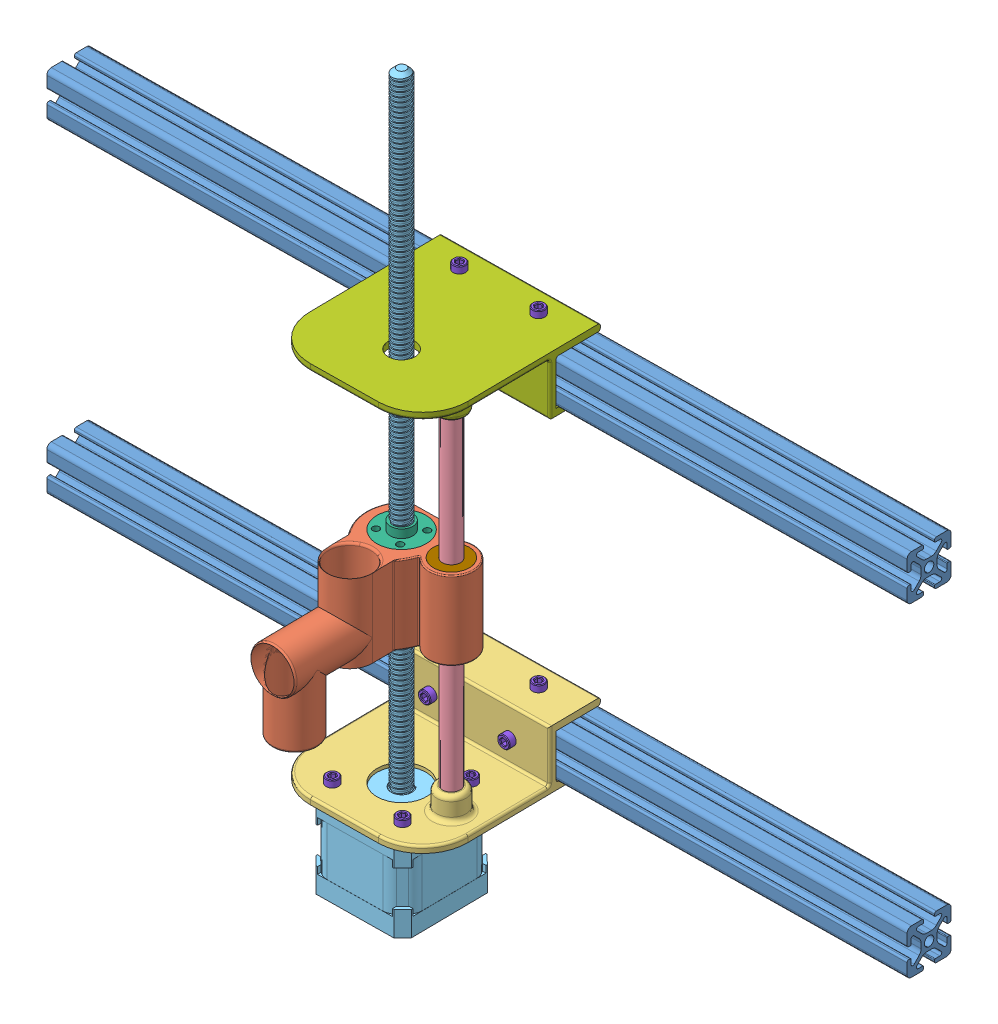
SolidWorks assembly Assem2, configuration Default. Lengths in mm.
Overall size (380.24 318.5 115.27).
26 component instances, 9 part files, 62 mates.
Components (placement in the parent):
- 8020-380.020400mm-1: 8020-380.020400mm [Default] at (296.7337 127.1693 232.1111) x (0.012782 0 0.999918) z (-0.999918 0 0.012782) size (19.99 19.99 380.02)
- Part3-1: Part3 [Default] at (107.463 220.2256 291.1801) x (-0.999918 0 0.012782) z (-0.012782 0 -0.999918) size (48.24 55.74 71)
- Part4-1: Part4 [Default] at (107.1224 114.1744 264.5322) x (0.012782 0 0.999918) z (-0.999918 0 0.012782) size (80 26 70)
- Part2-1: Part2 [Default] at (129.3015 117.1744 278.3999) x (0.999993 0 -0.003845) z (0.003845 0 0.999993) size (8 165 8)
- Pololu Stepper with 280mm LeadScrew-1: Pololu Stepper with 280mm LeadScrew [Valor predeterminado] at (107.3033 106.1744 278.6811) x (0.999918 0 -0.012782) z (0.012782 0 0.999918) size (42.3 318.5 42.3)
- TravelingNut-1: TravelingNut [Valor predeterminado] at (107.3033 213.2256 278.6811) x (0.998376 0 0.056964) z (-0.056964 0 0.998376) size (22 13.66 22)
- Part5-1: Part5 [Default] at (107.1224 285.154 264.5322) x (0.012782 0 0.999918) z (0.999918 0 -0.012782) size (80 26 70)
- 8020-380.020400mm-2: 8020-380.020400mm [Default] at (296.7337 272.1591 232.1111) x (0 1 0) z (-0.999918 0 0.012782) size (19.99 19.99 380.02)
- M3x10-1: M3x10 [Default] at (123.0001 120.1744 293.9817) x (0 -1 0) z (0.006337 0 0.99998) size (13 5.5 5.5)
- M3x10-2: M3x10 [Default] at (122.6039 120.1744 262.9842) x (0 -1 0) z (0 0 1) size (13 5.5 5.5)
- M3x10-3: M3x10 [Default] at (91.6064 120.1744 263.3805) x (0 -1 0) z (0 0 1) size (13 5.5 5.5)
- M3x10-4: M3x10 [Default] at (92.0026 120.1744 294.3779) x (0 -1 0) z (0 0 1) size (13 5.5 5.5)
- M3x10-5: M3x10 [Default] at (89.4449 127.1744 250.7571) x (-0.012782 0 -0.999918) z (0.974465 -0.224194 -0.012456) size (13 5.5 5.5)
- M3x10-6: M3x10 [Default] at (124.442 127.1744 250.3097) x (-0.012782 0 -0.999918) z (0.974868 -0.222434 -0.012462) size (13 5.5 5.5)
- M3x10-7: M3x10 [Default] at (124.2375 143.1744 234.311) x (0 -1 0) z (0 0 1) size (13 5.5 5.5)
- M3x10-8: M3x10 [Default] at (89.2404 143.1744 234.7584) x (0 -1 0) z (0 0 1) size (13 5.5 5.5)
- M3x10-9: M3x10 [Default] at (89.4449 272.154 250.7571) x (-0.012782 0 -0.999918) z (0.982593 0.185347 -0.01256) size (13 5.5 5.5)
- M3x10-10: M3x10 [Default] at (124.442 272.154 250.3097) x (-0.012782 0 -0.999918) z (0.982593 0.185347 -0.01256) size (13 5.5 5.5)
- M3x10-11: M3x10 [Default] at (124.2375 288.154 234.311) x (0 -1 0) z (-0.816398 0 -0.57749) size (13 5.5 5.5)
- M3x10-12: M3x10 [Default] at (89.2404 256.154 234.7584) x (0 1 0) z (0.795512 0 0.605938) size (13 5.5 5.5)
- M3x10-13: M3x10 [Default] at (89.2404 288.154 234.7584) x (0 -1 0) z (0.325387 0 -0.945581) size (13 5.5 5.5)
- M3x10-14: M3x10 [Default] at (124.2375 256.154 234.311) x (0 1 0) z (0 0 1) size (13 5.5 5.5)
- M3x10-15: M3x10 [Default] at (124.2375 111.1744 234.311) x (0 1 0) z (0 0 1) size (13 5.5 5.5)
- M3x10-16: M3x10 [Default] at (89.2404 111.1744 234.7584) x (0 1 0) z (0 0 1) size (13 5.5 5.5)
- 6659K679_OIL-EMBEDDED FLANGED SLEEVE BEARING-1: 6659K679_OIL-EMBEDDED FLANGED SLEEVE BEARING [6659K679] at (129.3015 180.2256 278.3999) size (16 16 16)
- 6659K679_OIL-EMBEDDED FLANGED SLEEVE BEARING-2: 6659K679_OIL-EMBEDDED FLANGED SLEEVE BEARING [6659K679] at (129.3015 215.2256 278.3999) x (-0.523048 0 -0.852303) z (-0.852303 0 0.523048) size (16 16 16)
Mates (geometry in assembly coordinates):
- Width1: width anti-aligned: plane of 8020-380.020400mm-1 through (-83.2702 133.7944 235.8351) normal (-0.999918 0 0.012782); plane of Part4-1 through (296.7192 133.7944 230.9778) normal (0.999918 0 -0.012782); plane of 8020-380.020400mm-1 through (142.1195 117.1744 264.0849) normal (0.999918 0 -0.012782); plane of Part4-1 through (72.1253 117.1744 264.9796) normal (-0.999918 0 0.012782)
- Coincident23: coincident anti-aligned: plane of 8020-380.020400mm-1 through (-83.3578 117.1744 228.9808) normal (0 -1 0); plane of Part4-1 through (107.1224 117.1744 264.5322) normal (0 1 0)
- Coincident24: coincident anti-aligned: plane of 8020-380.020400mm-1 through (-83.1279 119.181 246.9625) normal (0.012782 0 0.999918); plane of Part4-1 through (106.8668 140.1744 244.5339) normal (-0.012782 0 -0.999918)
- Parallel3: parallel aligned: plane of 8020-380.020400mm-1 through (-83.1536 137.1642 244.9561) normal (0 1 0); plane of 8020-380.020400mm-2 through (-83.1536 282.154 244.9561) normal (0 1 0)
- Distance2: distance = 125 mm anti-aligned: plane of 8020-380.020400mm-2 through (-83.3578 262.1642 228.9808) normal (0 -1 0); plane of 8020-380.020400mm-1 through (-83.3578 137.1642 228.9808) normal (0 1 0)
- Coincident33: coincident aligned: plane of 8020-380.020400mm-1 through (-83.1279 135.1576 246.9625) normal (0.012782 0 0.999918); plane of 8020-380.020400mm-2 through (-83.1279 264.1708 246.9625) normal (0.012782 0 0.999918)
- Coincident34: coincident aligned: plane of 8020-380.020400mm-1 through (-83.2702 133.7944 235.8351) normal (-0.999918 0 0.012782); plane of 8020-380.020400mm-2 through (-83.3403 271.0257 230.3439) normal (-0.999918 0 0.012782)
- Concentric14: concentric anti-aligned: cylinder of Part3-1 through (107.3033 211.2256 278.6811) axis (0 1 0) radius 11; cylinder of TravelingNut-1 through (107.3033 215.2256 278.6811) axis (0 -1 0) radius 11
- Coincident19: coincident anti-aligned: plane of Part3-1 through (107.463 211.2256 291.1801) normal (0 1 0); plane of TravelingNut-1 through (107.3033 211.2256 278.6811) normal (0 -1 0)
- Concentric39: concentric anti-aligned: cylinder of Part3-1 through (129.3015 199.2256 278.3999) axis (0 1 0) radius 6; cylinder of Part7-2 through (129.3015 215.2256 278.3999) axis (0 -1 0) radius 6
- Coincident63: coincident anti-aligned: plane of Part3-1 through (107.463 199.2256 291.1801) normal (0 1 0); plane of Part7-2 through (129.3015 199.2256 278.3999) normal (0 -1 0)
- Concentric41: concentric aligned: cylinder of Part3-1 through (129.3015 196.2256 278.3999) axis (0 -1 0) radius 6; cylinder of Part7-1 through (129.3015 196.2256 278.3999) axis (0 -1 0) radius 6
- Coincident65: coincident anti-aligned: plane of Part3-1 through (107.463 196.2256 291.1801) normal (0 -1 0); plane of Part7-1 through (129.3015 196.2256 278.3999) normal (0 1 0)
- Coincident18: coincident anti-aligned: plane of Part4-1 through (107.1224 114.1744 264.5322) normal (0 -1 0); plane of Pololu Stepper with 280mm LeadScrew-1 through (107.3033 114.1744 278.6811) normal (0 1 0)
- Concentric11: concentric anti-aligned: cylinder of Part4-1 through (107.3033 107.1744 278.6811) axis (0 1 0) radius 11.025; cylinder of Pololu Stepper with 280mm LeadScrew-1 through (107.3033 115.6744 278.6811) axis (0 -1 0) radius 11
- Concentric12: concentric aligned: circle of Part4-1; cylinder of Pololu Stepper with 280mm LeadScrew-1 through (92.0026 89.1744 294.3779) axis (0 1 0) radius 1.8537
- Concentric16: concentric aligned: cylinder of Part4-1 through (129.3015 127.1744 278.3999) axis (0 -1 0) radius 4; cylinder of Part2-1 through (129.3015 282.1744 278.3999) axis (0 -1 0) radius 4
- Coincident30: coincident anti-aligned: plane of Part4-1 through (107.1224 117.1744 264.5322) normal (0 1 0); plane of Part2-1 through (129.3015 117.1744 278.3999) normal (0 -1 0)
- Concentric21: concentric aligned: cylinder of Part4-1 through (123.0001 107.1744 293.9817) axis (0 1 0) radius 1.5; cylinder of M3x10-1 through (123.0001 208.8799 293.9817) axis (0 1 0) radius 2.75
- Coincident43: coincident anti-aligned: plane of Part4-1 through (107.1224 117.1744 264.5322) normal (0 1 0); plane of M3x10-4 through (93.4926 117.1744 294.3779) normal (0 -1 0)
- Concentric22: concentric aligned: cylinder of Part4-1 through (92.0026 107.1744 294.3779) axis (0 1 0) radius 1.5; cylinder of M3x10-4 through (92.0026 208.8799 294.3779) axis (0 1 0) radius 2.75
- Coincident44: coincident anti-aligned: plane of Part4-1 through (107.1224 117.1744 264.5322) normal (0 1 0); plane of M3x10-1 through (124.4901 117.1744 293.9723) normal (0 -1 0)
- Coincident45: coincident anti-aligned: plane of Part4-1 through (107.1224 117.1744 264.5322) normal (0 1 0); plane of M3x10-3 through (93.0964 117.1744 263.3805) normal (0 -1 0)
- Concentric23: concentric aligned: cylinder of Part4-1 through (91.6064 107.1744 263.3805) axis (0 1 0) radius 1.5; cylinder of M3x10-3 through (91.6064 208.8799 263.3805) axis (0 1 0) radius 2.75
- Coincident46: coincident anti-aligned: plane of Part4-1 through (107.1224 117.1744 264.5322) normal (0 1 0); plane of M3x10-2 through (124.0939 117.1744 262.9842) normal (0 -1 0)
- Concentric24: concentric aligned: cylinder of Part4-1 through (122.6039 107.1744 262.9842) axis (0 1 0) radius 1.5; cylinder of M3x10-2 through (122.6039 208.8799 262.9842) axis (0 1 0) radius 2.75
- Coincident48: coincident anti-aligned: plane of Part4-1 through (106.9051 140.1744 247.5336) normal (0.012782 0 0.999918); plane of M3x10-5 through (89.7406 128.6265 247.753) normal (-0.012782 0 -0.999918)
- Concentric25: concentric aligned: cylinder of Part4-1 through (89.1893 127.1744 230.7587) axis (0.012782 0 0.999918) radius 2.5; cylinder of M3x10-5 through (90.5787 127.1744 339.4553) axis (0.012782 0 0.999918) radius 2.75
- Coincident50: coincident anti-aligned: plane of Part4-1 through (106.9051 140.1744 247.5336) normal (0.012782 0 0.999918); plane of M3x10-6 through (124.7351 128.6271 247.3057) normal (-0.012782 0 -0.999918)
- Concentric26: concentric aligned: cylinder of Part4-1 through (124.1864 127.1744 230.3113) axis (0.012782 0 0.999918) radius 2.5; cylinder of M3x10-6 through (125.5758 127.1744 339.0079) axis (0.012782 0 0.999918) radius 2.75
- Coincident51: coincident anti-aligned: plane of Part4-1 through (107.1224 140.1744 264.5322) normal (0 1 0); plane of M3x10-8 through (90.7304 140.1744 234.7584) normal (0 -1 0)
- Concentric27: concentric aligned: cylinder of Part4-1 through (89.2404 137.1744 234.7584) axis (0 1 0) radius 2.5; cylinder of M3x10-8 through (89.2404 231.8799 234.7584) axis (0 1 0) radius 2.75
- Coincident52: coincident anti-aligned: plane of Part4-1 through (107.1224 140.1744 264.5322) normal (0 1 0); plane of M3x10-7 through (125.7275 140.1744 234.311) normal (0 -1 0)
- Concentric28: concentric aligned: cylinder of Part4-1 through (124.2375 137.1744 234.311) axis (0 1 0) radius 2.5; cylinder of M3x10-7 through (124.2375 231.8799 234.311) axis (0 1 0) radius 2.75
- Coincident61: coincident anti-aligned: plane of Part4-1 through (107.1224 114.1744 264.5322) normal (0 -1 0); plane of M3x10-15 through (122.7475 114.1744 234.311) normal (0 1 0)
- Concentric37: concentric aligned: cylinder of Part4-1 through (124.2375 117.1744 234.311) axis (0 -1 0) radius 2.5; cylinder of M3x10-15 through (124.2375 22.4689 234.311) axis (0 -1 0) radius 2.75
- Coincident62: coincident anti-aligned: plane of Part4-1 through (107.1224 114.1744 264.5322) normal (0 -1 0); plane of M3x10-16 through (87.7504 114.1744 234.7584) normal (0 1 0)
- Concentric38: concentric aligned: cylinder of Part4-1 through (89.2404 117.1744 234.7584) axis (0 -1 0) radius 2.5; cylinder of M3x10-16 through (89.2404 22.4689 234.7584) axis (0 -1 0) radius 2.75
- Concentric42: concentric aligned: cylinder of Part2-1 through (129.3015 282.1744 278.3999) axis (0 -1 0) radius 4; cylinder of Part7-2 through (129.3015 215.2256 278.3999) axis (0 -1 0) radius 4
- Concentric13: concentric anti-aligned: cone of Pololu Stepper with 280mm LeadScrew-1 through (107.3033 394.1744 278.6811) axis (0 1 0); cylinder of TravelingNut-1 through (107.3033 215.2256 278.6811) axis (0 -1 0) radius 11
- Coincident31: coincident anti-aligned: plane of Part5-1 through (106.8668 259.154 244.5339) normal (-0.012782 0 -0.999918); plane of 8020-380.020400mm-2 through (-83.1279 280.1474 246.9625) normal (0.012782 0 0.999918)
- Coincident32: coincident anti-aligned: plane of Part5-1 through (107.1224 282.154 264.5322) normal (0 -1 0); plane of 8020-380.020400mm-2 through (-83.1536 282.154 244.9561) normal (0 1 0)
- Width2: width anti-aligned: plane of 8020-380.020400mm-2 through (296.649 271.0257 225.4865) normal (0.999918 0 -0.012782); plane of Part5-1 through (-83.3403 271.0257 230.3439) normal (-0.999918 0 0.012782); plane of 8020-380.020400mm-2 through (72.1253 282.154 264.9796) normal (-0.999918 0 0.012782); plane of Part5-1 through (142.1195 282.154 264.0849) normal (0.999918 0 -0.012782)
- Coincident35: coincident anti-aligned: plane of Part5-1 through (107.1224 282.154 264.5322) normal (0 -1 0); plane of 5972K910_BALL BEARING-1 through (107.5467 282.154 268.0339) normal (0 1 0)
- Coincident38: coincident anti-aligned: plane of Part5-1 through (113.8675 274.1761 266.5189) normal (0 -1 0); plane of part 6-1 through (114.0483 274.1761 280.6677) normal (0 1 0)
- Concentric20: concentric anti-aligned: cylinder of Part5-1 through (114.0483 274.1761 280.6677) axis (0 -1 0) radius 11.75; cylinder of part 6-1 through (114.0483 272.1761 280.6677) axis (0 1 0) radius 11.75
- Coincident54: coincident anti-aligned: plane of Part5-1 through (106.9051 259.154 247.5336) normal (0.012782 0 0.999918); plane of M3x10-9 through (89.1304 273.6182 247.7608) normal (-0.012782 0 -0.999918)
- Concentric30: concentric aligned: cylinder of Part5-1 through (89.1893 272.154 230.7587) axis (0.012782 0 0.999918) radius 2.5; cylinder of M3x10-9 through (90.5787 272.154 339.4553) axis (0.012782 0 0.999918) radius 2.75
- Coincident55: coincident anti-aligned: plane of Part5-1 through (106.9051 259.154 247.5336) normal (0.012782 0 0.999918); plane of M3x10-10 through (124.1275 273.6182 247.3135) normal (-0.012782 0 -0.999918)
- Concentric31: concentric aligned: cylinder of Part5-1 through (124.1864 272.154 230.3113) axis (0.012782 0 0.999918) radius 2.5; cylinder of M3x10-10 through (125.5758 272.154 339.0079) axis (0.012782 0 0.999918) radius 2.75
- Coincident57: coincident anti-aligned: plane of Part5-1 through (107.1224 285.154 264.5322) normal (0 1 0); plane of M3x10-13 through (87.8315 285.154 234.2735) normal (0 -1 0)
- Concentric33: concentric aligned: cylinder of Part5-1 through (89.2404 282.154 234.7584) axis (0 1 0) radius 2.5; cylinder of M3x10-13 through (89.2404 376.8595 234.7584) axis (0 1 0) radius 2.75
- Coincident58: coincident anti-aligned: plane of Part5-1 through (107.1224 285.154 264.5322) normal (0 1 0); plane of M3x10-11 through (123.3771 285.154 235.5274) normal (0 -1 0)
- Concentric34: concentric aligned: cylinder of Part5-1 through (124.2375 282.154 234.311) axis (0 1 0) radius 2.5; cylinder of M3x10-11 through (124.2375 376.8595 234.311) axis (0 1 0) radius 2.75
- Coincident59: coincident anti-aligned: plane of Part5-1 through (107.1224 259.154 264.5322) normal (0 -1 0); plane of M3x10-12 through (88.3375 259.154 235.9437) normal (0 1 0)
- Concentric35: concentric aligned: cylinder of Part5-1 through (89.2404 262.154 234.7584) axis (0 -1 0) radius 2.5; cylinder of M3x10-12 through (89.2404 167.4485 234.7584) axis (0 -1 0) radius 2.75
- Coincident60: coincident anti-aligned: plane of Part5-1 through (107.1224 259.154 264.5322) normal (0 -1 0); plane of M3x10-14 through (122.7475 259.154 234.311) normal (0 1 0)
- Concentric36: concentric aligned: circle of Part5-1; cylinder of M3x10-14 through (124.2375 167.4485 234.311) axis (0 -1 0) radius 2.75
- Coincident66: coincident anti-aligned: plane of Part3-1 through (107.463 196.2256 291.1801) normal (0 -1 0); plane of 6659K679_OIL-EMBEDDED FLANGED SLEEVE BEARING-1 through (129.3015 196.2256 278.3999) normal (0 1 0)
- Concentric43: concentric aligned: cylinder of Part3-1 through (129.3015 196.2256 278.3999) axis (0 -1 0) radius 6; cylinder of 6659K679_OIL-EMBEDDED FLANGED SLEEVE BEARING-1 through (129.3015 196.2256 278.3999) axis (0 -1 0) radius 6.015
- Coincident67: coincident anti-aligned: plane of Part3-1 through (107.463 199.2256 291.1801) normal (0 1 0); plane of 6659K679_OIL-EMBEDDED FLANGED SLEEVE BEARING-2 through (129.3015 199.2256 278.3999) normal (0 -1 0)
- Concentric44: concentric aligned: circle of 6659K679_OIL-EMBEDDED FLANGED SLEEVE BEARING-1; cylinder of 6659K679_OIL-EMBEDDED FLANGED SLEEVE BEARING-2 through (129.3015 199.2256 278.3999) axis (0 1 0) radius 4.005
